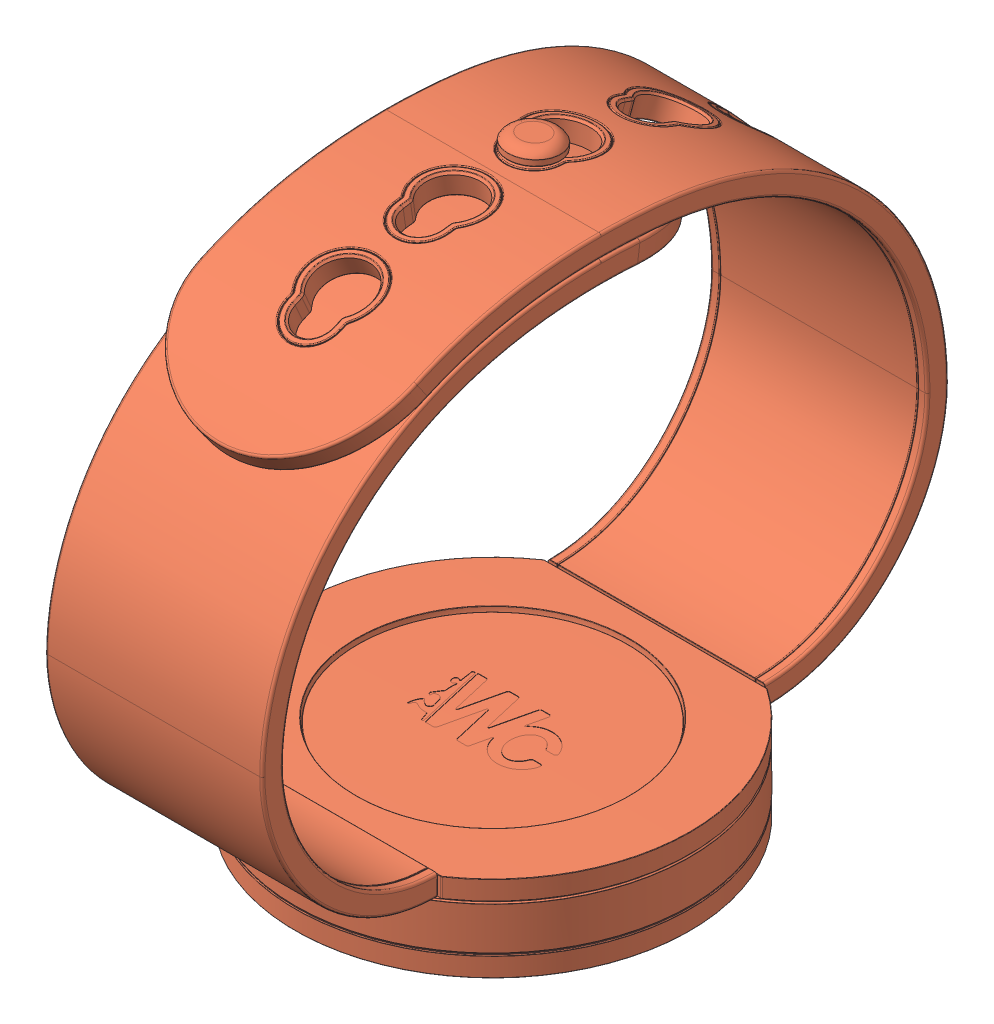
SolidWorks assembly watch-assem_06, configuration Default. Lengths in mm.
Overall size (48.83 68.76 87.1).
2 component instances, 2 part files, 3 mates.
Components (placement in the parent):
- mech-X14-1: mech-X14 [Default] at (-2.3352 2.8757 -0.7215) size (36.7 5.15 36)
- RISE-watch_X1-1: RISE-watch_X1 [Default] at (-2.3352 -2.9743 -0.7215) x (-1 0 0) z (0 0 1) size (48.83 68.76 87.1)
Mates (geometry in assembly coordinates):
- Coincident2: coincident aligned: plane of mech-X14-1 through (-2.3352 2.8757 -0.7215) normal (0 0 1); plane of RISE-watch_X1-1 through (-2.3352 -2.9743 -0.7215) normal (0 0 1)
- Coincident3: coincident anti-aligned: plane of mech-X14-1 through (-2.3352 2.8757 -0.7215) normal (1 0 0); plane of RISE-watch_X1-1
- Distance1: distance = 0.1 mm anti-aligned: plane of RISE-watch_X1-1 through (-2.3352 -0.3743 -0.7215) normal (0 1 0); plane of mech-X14-1 through (2.0695 -0.2743 2.9746) normal (0 -1 0)
